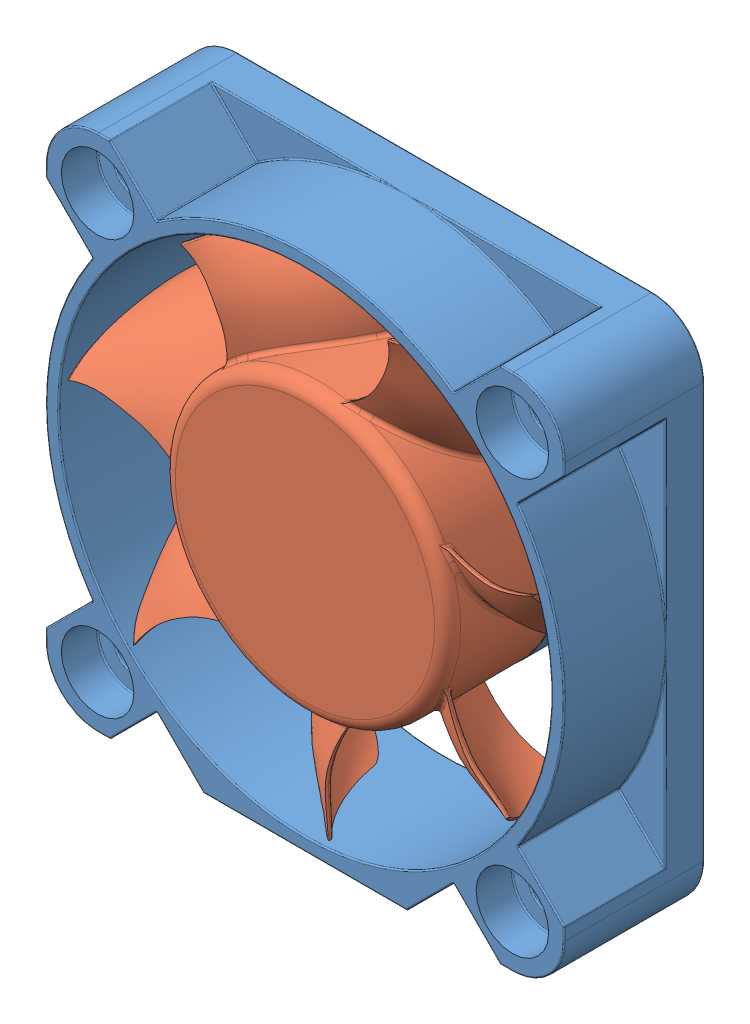
SolidWorks assembly Jamicon_KF0410-01, configuration По умолчанию. Lengths in mm.
Overall size (52.6 52.59 10.82).
2 component instances, 2 part files, 3 mates.
Components (placement in the parent):
- Jamicon_KF0410-01_Case-1: Jamicon_KF0410-01_Case [Default] at origin size (40.01 40.11 10.81)
- Jamicon_KF0410-01_Rotor-1: Jamicon_KF0410-01_Rotor [Default] at (0 0 -1) x (0.720673 0.693275 0) z (0 0 1) size (37.4 37 9.12)
Mates (geometry in assembly coordinates):
- Concentric1: concentric anti-aligned: cylinder of Jamicon_KF0410-01_Case-1 through (0 0 7.7) axis (0 0 -1) radius 19; line of Jamicon_KF0410-01_Rotor-1 through (0 0 -1) axis (0 0 1)
- Distance1: distance = 0 mm aligned: plane of Jamicon_KF0410-01_Rotor-1 through (0 0 7.8) normal (0 0 1); plane of Jamicon_KF0410-01_Case-1 through (-0.0001 -0.2732 7.8) normal (0 0 1)
- Lock1: lock: unknown of Jamicon_KF0410-01_Case-1
